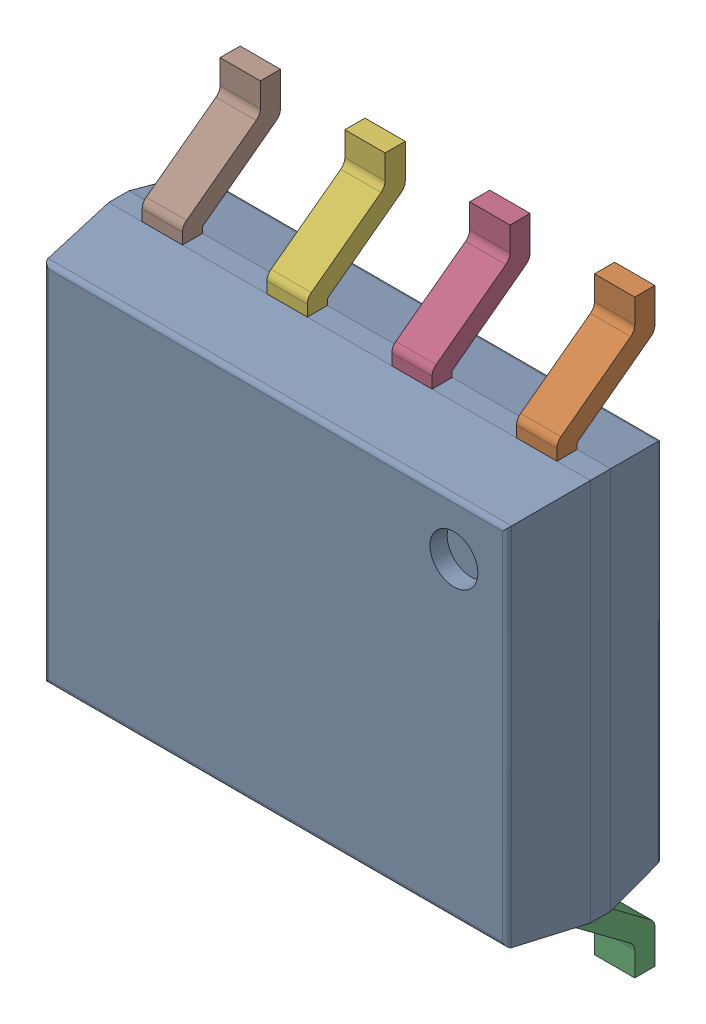
SolidWorks assembly IC8_1.step, configuration Default. Lengths in mm.
Overall size (4.9 6 1.75).
3 component instances, 2 part files, 0 mates.
Components (placement in the parent):
- 6348793408_1.step-3: 6348793408_1.step [Default] at (367.9567 250.8316 0) x (0 -1 0) z (0 0 1) size (6 4.9 1.75)
  - Body-1216_1.step-5: Body-1216_1.step [Default] at origin size (3.9 4.9 1.57)
  - PinsArrayLR-1217_1.step-5: PinsArrayLR-1217_1.step [Default] at origin size (6 4.22 1)
